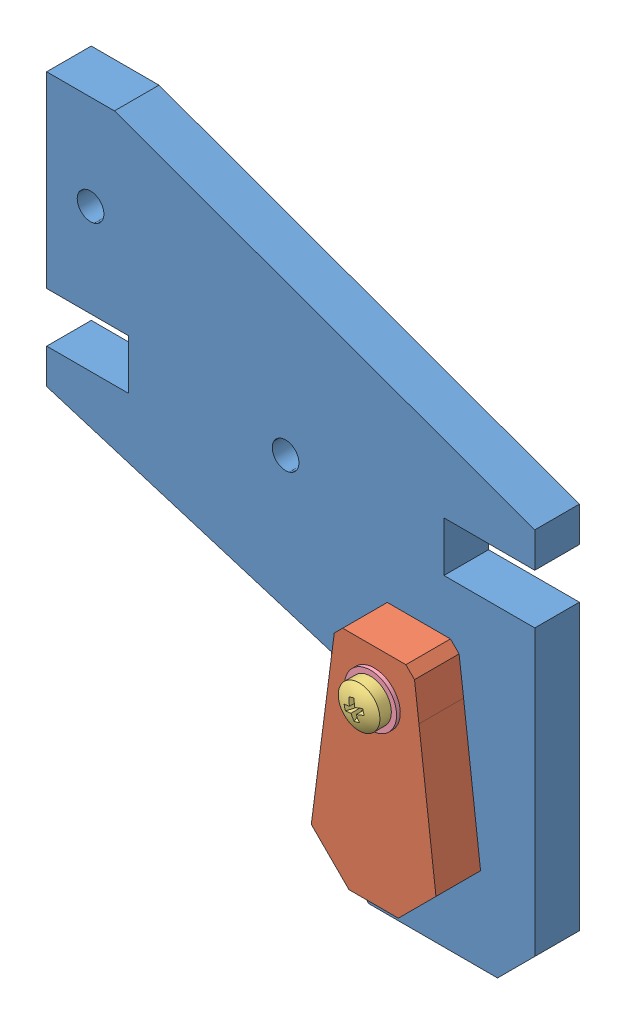
SolidWorks assembly Assembly Z-Top Right, configuration Valor predeterminado. Lengths in mm.
Overall size (65.68 75.26 18.37).
7 component instances, 5 part files, 12 mates.
Components (placement in the parent):
- Z-Top-1: Z-Top [Valor predeterminado] at (60.5517 37.2517 0) x (-1 0 0) z (0 0 1) size (65.68 75.26 6)
- Z-Smooth Rod Constraint-1: Z-Smooth Rod Constraint [Valor predeterminado] at (-22.2402 -51.9169 6) size (16.77 30.05 6)
- Assembly Screw DIN 7985 - M3 x 16 --- 16N + Washer DIN 125A - M3-1: Assembly Screw DIN 7985 - M3 x 16 --- 16N + Washer DIN 125A - M3 [Valor predeterminado] at (0.1593 -21.3221 8.6091) x (0 0 1) z (0.960687 0.277632 0) size (18.37 7 7)
  - Screw DIN 7985 - M3 x 16 --- 16N-1: Screw DIN 7985 - M3 x 16 --- 16N [Valor predeterminado] at (6.2909 0.1077 18.3725) size (18.37 5.6 5.6)
  - Washer DIN 125A - M3-1: Washer DIN 125A - M3 [Valor predeterminado] at (3.3909 0.1077 18.3725) size (0.5 7 7)
- Nut DIN 934 - M3-1: Nut DIN 934 - M3 [Valor predeterminado] at (17.8395 -16.3247 -1.7) x (0 0 1) z (-0.850278 -0.526333 0) size (2.4 5.5 6.35)
- Washer DIN 125A - M3-1: Washer DIN 125A - M3 [Valor predeterminado] at (17.8395 -16.3247 -0.5) x (0 0 1) z (-0.965276 -0.261234 0) size (0.5 7 7)
Mates (geometry in assembly coordinates):
- Simétrico3: symmetric: plane of assembly; plane of assembly; plane of Z-Top-1 through (-21.2131 3.3573 6) normal (0 -1 0); plane of Z-Top-1 through (-32.2356 -3.3573 6) normal (0 1 0); plane of assembly
- Coincidente1: coincident: plane of assembly; plane of Z-Top-1 through (60.5517 37.2517 0) normal (0 0 -1); plane of assembly
- Simétrico4: symmetric: plane of assembly; plane of assembly; plane of Z-Top-1 through (21.2131 3.3573 6) normal (1 0 0); plane of Z-Top-1 through (-21.2131 -3.3573 6) normal (-1 0 0); plane of assembly
- Coincidente2: coincident: plane of assembly; plane of assembly; plane of Z-Top-1 through (60.5517 37.2517 6) normal (0 0 1); plane of Z-Smooth Rod Constraint-1 through (-22.2402 -51.9169 6) normal (0 0 -1)
- Concêntrico1: concentric: cylinder of assembly; cylinder of assembly; cylinder of Z-Top-1 through (17.8395 -16.3247 6) axis (0 0 -1) radius 1.8; cylinder of Z-Smooth Rod Constraint-1 through (17.8395 -16.3247 12) axis (0 0 -1) radius 1.8
- Paralelo1: parallel: plane of assembly; plane of Z-Smooth Rod Constraint-1 through (22.0908 -10.3112 12) normal (0 1 0); plane of assembly
- Coincidente3: coincident: plane of Z-Smooth Rod Constraint-1 through (-22.2402 -51.9169 12) normal (0 0 1); plane of Assembly Screw DIN 7985 - M3 x 16 --- 16N + Washer DIN 125A - M3-1/Washer DIN 125A - M3-1 through (17.8395 -16.3247 12) normal (0 0 -1)
- Concêntrico2: concentric: cylinder of assembly; cylinder of assembly; cylinder of Z-Smooth Rod Constraint-1 through (17.8395 -16.3247 12) axis (0 0 -1) radius 1.8; cylinder of Assembly Screw DIN 7985 - M3 x 16 --- 16N + Washer DIN 125A - M3-1/Screw DIN 7985 - M3 x 16 --- 16N-1 through (17.8395 -16.3247 14.9) axis (0 0 1) radius 1.5
- Coincidente4: coincident: plane of assembly; plane of assembly; plane of Z-Top-1 through (60.5517 37.2517 0) normal (0 0 -1); plane of Washer DIN 125A - M3-1 through (17.8395 -16.3247 0) normal (0 0 1)
- Concêntrico3: concentric: cylinder of assembly; cylinder of assembly; cylinder of Assembly Screw DIN 7985 - M3 x 16 --- 16N + Washer DIN 125A - M3-1/Screw DIN 7985 - M3 x 16 --- 16N-1 through (17.8395 -16.3247 14.9) axis (0 0 1) radius 1.5; cylinder of Washer DIN 125A - M3-1 through (17.8395 -16.3247 0) axis (0 0 -1) radius 1.6
- Coincidente5: coincident: plane of assembly; plane of assembly; plane of Nut DIN 934 - M3-1 through (20.6369 -17.8273 -0.5) normal (0 0 1); plane of Washer DIN 125A - M3-1 through (17.8395 -16.3247 -0.5) normal (0 0 -1)
- Concêntrico4: concentric: cylinder of assembly; cylinder of assembly; cylinder of Assembly Screw DIN 7985 - M3 x 16 --- 16N + Washer DIN 125A - M3-1/Screw DIN 7985 - M3 x 16 --- 16N-1 through (17.8395 -16.3247 14.9) axis (0 0 1) radius 1.5; cylinder of Nut DIN 934 - M3-1 through (17.8395 -16.3247 -0.5) axis (0 0 -1) radius 1.25
